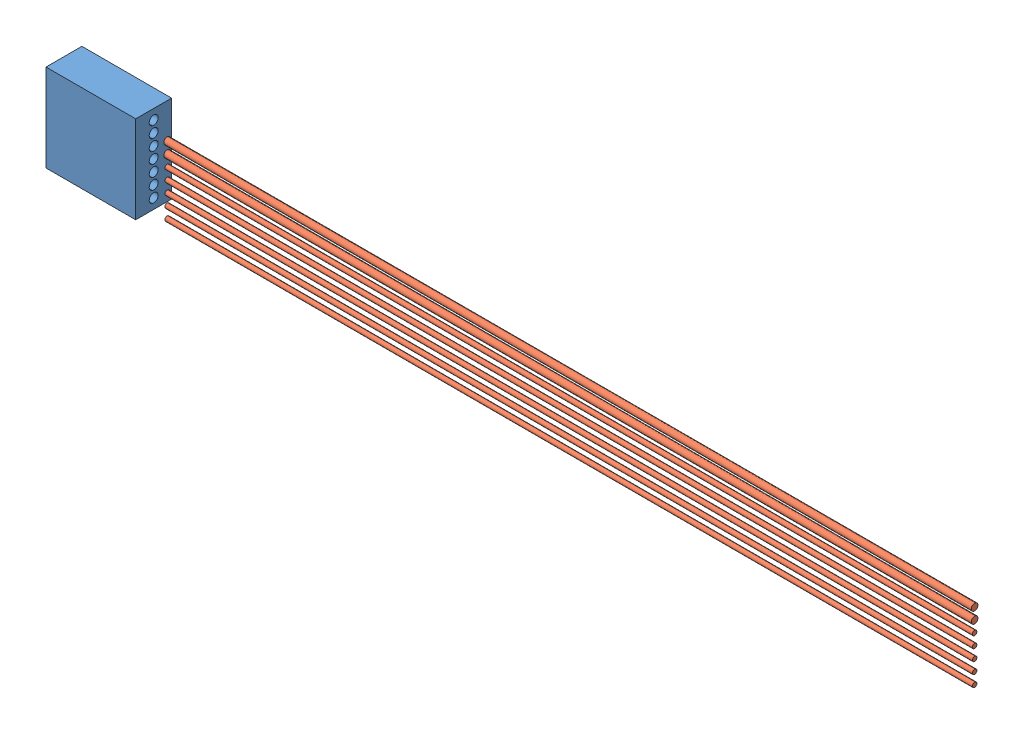
SolidWorks assembly Harness_22-CABLE_REALOP_ONE_ASSEMBLY, configuration AnnotateFlattenedRoute1 - Default. Lengths in mm.
Overall size (101.5 10.13 4).
3 component instances, 3 part files, 1 mates.
Components (placement in the parent):
- 7_PIN-1: 7_PIN [Default] at (-11.5 -7.625 2) x (0 -1 0) z (1 0 0) size (9.75 4 20)
- Cable^Harness_22-CABLE_REALOP_ONE_ASSEMBLY-1: Cable^Harness_22-CABLE_REALOP_ONE_ASSEMBLY [Default] at origin size (79.18 57.24 111.46) (suppressed, hidden, virtual)
- Flattened_Cable^Harness_22-CABLE_REALOP_ONE_ASSEMBLY-1: Flattened_Cable^Harness_22-CABLE_REALOP_ONE_ASSEMBLY [Default] at origin (virtual)
Mates (geometry in assembly coordinates):
- Coincident901: coincident anti-aligned: plane of X_AND_Y_SOLAR_ARRAYS-1 through (188.3373 68.7975 271.1544) normal (0 -1 0); plane of 7_PIN-1 through (57.4435 68.7975 258.5027) normal (0 1 0)
